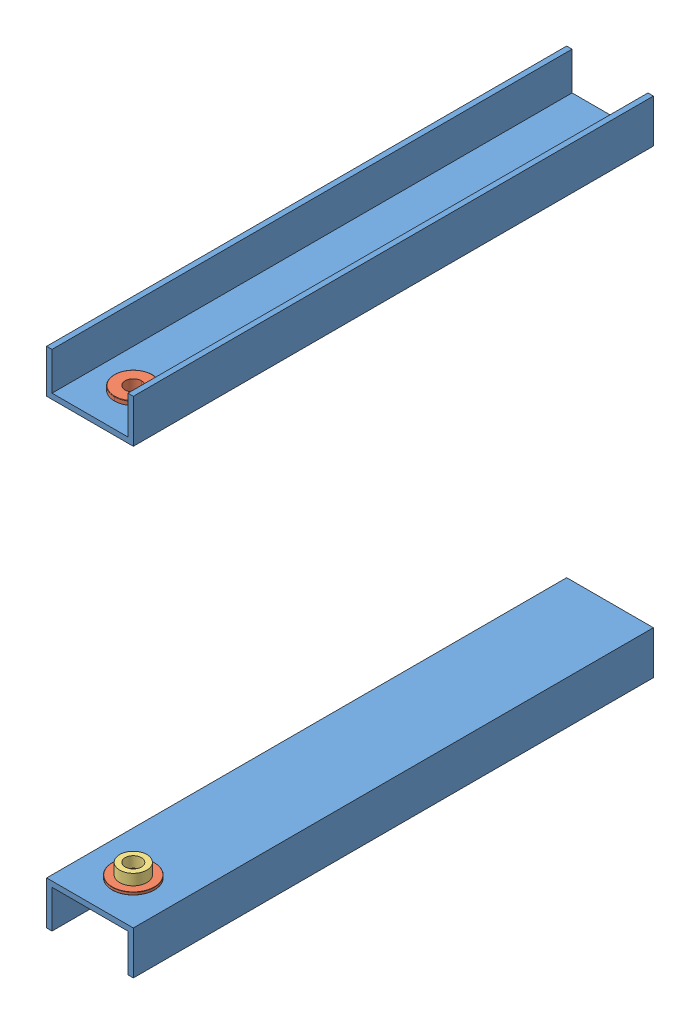
SolidWorks assembly Beaver Tail, configuration Default. Lengths in mm.
Overall size (50.8 295.25 304.8).
6 component instances, 3 part files, 11 mates.
Components (placement in the parent):
- Tail Bar A-1: Tail Bar A [Default] at (87.1226 210.9145 212.7952) size (50.8 25.4 304.8)
- am-0028 00.375'' id Flanged, Shielded Ball Bearing (FR6ZZ).step-1: am-0028 00.375'' id Flanged, Shielded Ball Bearing (FR6ZZ).step [Default] at (112.5226 209.3397 492.1952) size (24.77 7.11 24.77)
- spacer-1: spacer [Default] at (112.5226 202.9897 492.1952) size (15.88 6.35 15.88)
- Tail Bar A-3: Tail Bar A [Default] at (137.9226 -33.5351 212.7952) x (-1 0 0) z (0 0 1) size (50.8 25.4 304.8)
- am-0028 00.375'' id Flanged, Shielded Ball Bearing (FR6ZZ).step-3: am-0028 00.375'' id Flanged, Shielded Ball Bearing (FR6ZZ).step [Default] at (112.5226 -31.9603 492.1952) x (-0.837169 0 -0.546944) z (-0.546944 0 0.837169) size (24.77 7.11 24.77)
- spacer-3: spacer [Default] at (112.5226 -25.6103 492.1952) x (0.837169 0 0.546944) z (0.546944 0 -0.837169) size (15.88 6.35 15.88)
Mates (geometry in assembly coordinates):
- Concentric1: concentric anti-aligned: cylinder of Tail Bar A-1 through (112.5226 210.9145 492.1952) axis (0 1 0) radius 10.4775; cylinder of am-0028 00.375'' id Flanged, Shielded Ball Bearing (FR6ZZ).step-1 through (112.5226 209.3397 492.1952) axis (0 -1 0) radius 11.1125
- Coincident1: coincident anti-aligned: plane of Tail Bar A-1 through (87.1226 210.9145 517.5952) normal (0 -1 0); plane of am-0028 00.375'' id Flanged, Shielded Ball Bearing (FR6ZZ).step-1 through (123.6351 210.9145 492.1952) normal (0 1 0)
- Coincident5: coincident anti-aligned: circle of am-0028 00.375'' id Flanged, Shielded Ball Bearing (FR6ZZ).step-1; cylinder of spacer-1 through (112.5226 202.9897 492.1952) axis (0 1 0) radius 4.7625
- Coincident6: coincident anti-aligned: plane of am-0028 00.375'' id Flanged, Shielded Ball Bearing (FR6ZZ).step-1 through (117.2851 209.3397 492.1952) normal (0 -1 0); plane of spacer-1 through (112.5226 209.3397 492.1952) normal (0 1 0)
- Concentric5: concentric anti-aligned: cylinder of am-0028 00.375'' id Flanged, Shielded Ball Bearing (FR6ZZ).step-3 through (112.5226 -31.9603 492.1952) axis (0 1 0) radius 4.7625; cylinder of spacer-3 through (112.5226 -25.6103 492.1952) axis (0 -1 0) radius 4.7625
- Coincident7: coincident anti-aligned: plane of am-0028 00.375'' id Flanged, Shielded Ball Bearing (FR6ZZ).step-3 through (108.5356 -31.9603 489.5904) normal (0 1 0); plane of spacer-3 through (112.5226 -31.9603 492.1952) normal (0 -1 0)
- Concentric6: concentric anti-aligned: cylinder of Tail Bar A-3 through (112.5226 -33.5351 492.1952) axis (0 -1 0) radius 10.4775; cylinder of am-0028 00.375'' id Flanged, Shielded Ball Bearing (FR6ZZ).step-3 through (112.5226 -31.9603 492.1952) axis (0 1 0) radius 11.1125
- Coincident8: coincident anti-aligned: plane of Tail Bar A-3 through (137.9226 -33.5351 517.5952) normal (0 1 0); plane of am-0028 00.375'' id Flanged, Shielded Ball Bearing (FR6ZZ).step-3 through (103.2196 -33.5351 486.1173) normal (0 -1 0)
- Distance1: distance = 228.6 mm anti-aligned: plane of spacer-3 through (112.5226 -25.6103 492.1952) normal (0 1 0); plane of spacer-1 through (112.5226 202.9897 492.1952) normal (0 -1 0)
- Coincident10: coincident aligned: plane of Tail Bar A-1 through (87.1226 210.9145 517.5952) normal (0 0 1); plane of Tail Bar A-3 through (137.9226 -33.5351 517.5952) normal (0 0 1)
- Coincident11: coincident aligned: plane of Tail Bar A-1 through (87.1226 210.9145 517.5952) normal (-1 0 0); plane of Tail Bar A-3 through (87.1226 -33.5351 517.5952) normal (-1 0 0)
